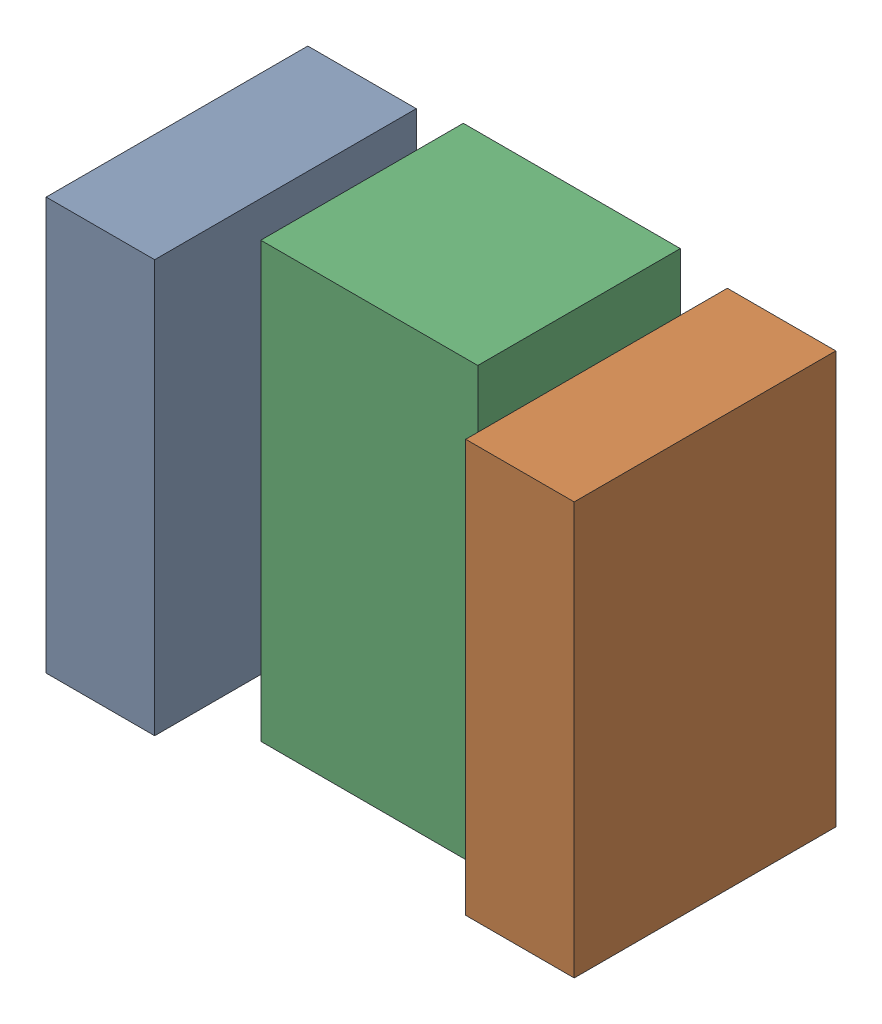
SolidWorks assembly C7_Motor_6Kanaloa_v2.0.0_Motor, configuration Default. Lengths in mm.
Overall size (3.65 3 1.81).
6 component instances, 2 part files, 0 mates.
Components (placement in the parent):
- 334788400-1: 334788400 [Default] at (59.468 139.192 0) size (0.75 2.85 1.81)
  - Extruded_5-1: Extruded_5 [Default] at origin size (0.75 2.85 1.81)
- 334788400-2: 334788400 [Default] at (62.368 139.192 0) size (0.75 2.85 1.81)
  - Extruded_5-1: Extruded_5 [Default] at origin size (0.75 2.85 1.81)
- 334788656-1: 334788656 [Default] at (60.918 139.192 0) size (1.5 3 1.4)
  - Extruded_1-1: Extruded_1 [Default] at origin size (1.5 3 1.4)
